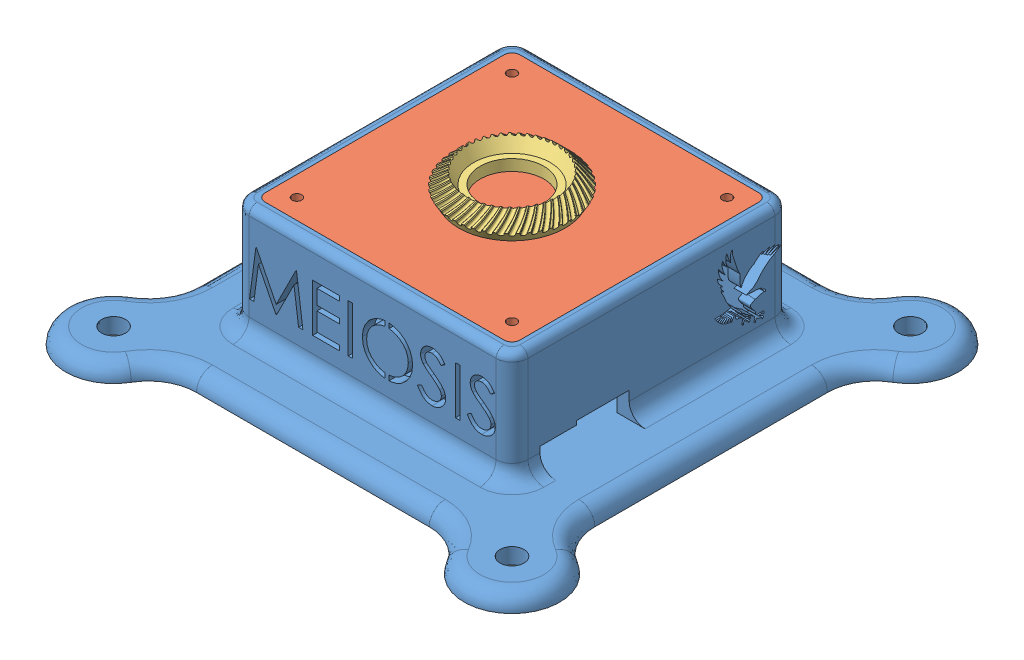
SolidWorks assembly Base, configuration Default. Lengths in mm.
Overall size (310 106.15 310).
3 component instances, 3 part files, 6 mates.
Components (placement in the parent):
- Base_Bottom-1: Base_Bottom [Default] at (-11.3923 154.1856 283.0049) size (310 80 310)
- Base_Top_diff-1: Base_Top_diff [Default] at (-11.3923 224.1856 283.0049) size (160 10 160)
- Bevel_Horizontal-1: Bevel_Horizontal [Défaut] at (-11.3923 234.1856 283.0049) size (79.84 26.15 74.98)
Mates (geometry in assembly coordinates):
- Coincident1: coincident anti-aligned: plane of Base_Bottom-1 through (-11.3923 224.1856 283.0049) normal (0 1 0); plane of Base_Top_diff-1 through (-11.3923 224.1856 283.0049) normal (0 -1 0)
- Coincident2: coincident anti-aligned: plane of Base_Bottom-1 through (-91.3923 234.1856 203.0049) normal (1 0 0); plane of Base_Top_diff-1 through (-91.3923 234.1856 203.0049) normal (-1 0 0)
- Coincident3: coincident anti-aligned: plane of Base_Bottom-1 through (-91.3923 234.1856 203.0049) normal (0 0 1); plane of Base_Top_diff-1 through (-91.3923 234.1856 203.0049) normal (0 0 -1)
- Coincident4: coincident anti-aligned: plane of Base_Top_diff-1 through (-11.3923 234.1856 283.0049) normal (0 1 0); plane of Bevel_Horizontal-1 through (-11.3923 234.1856 283.0049) normal (0 -1 0)
- Coincident5: coincident anti-aligned: circle of Base_Top_diff-1; circle of Bevel_Horizontal-1
- Coincident6: coincident anti-aligned: circle of Base_Top_diff-1; circle of Bevel_Horizontal-1
